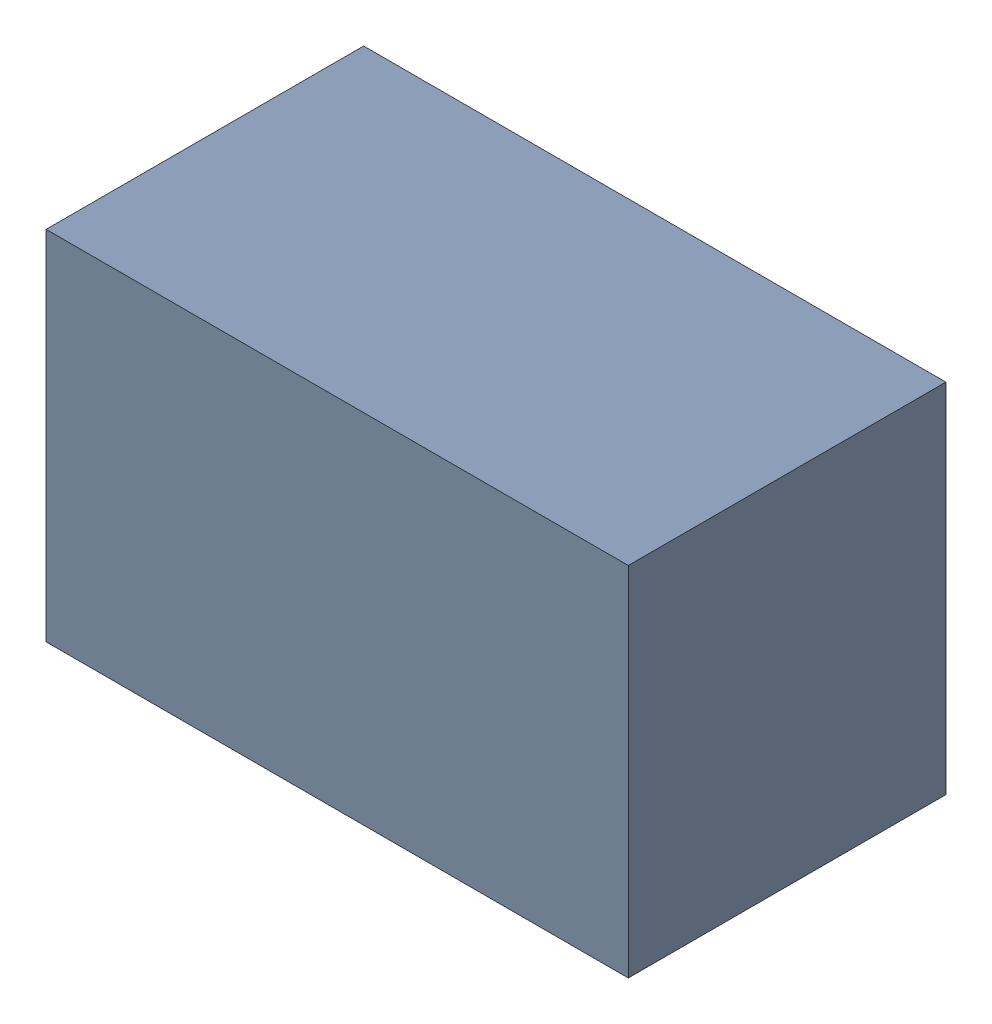
SolidWorks assembly CP3_1, configuration Default. Lengths in mm.
Overall size (2.2 1.35 1.2).
2 component instances, 1 part files, 0 mates.
Components (placement in the parent):
- 407988128-1: 407988128 [Default] at (73.279 2.54 0.0127) size (2.2 1.35 1.2)
  - Extruded_9-1: Extruded_9 [Default] at origin size (2.2 1.35 1.2)
